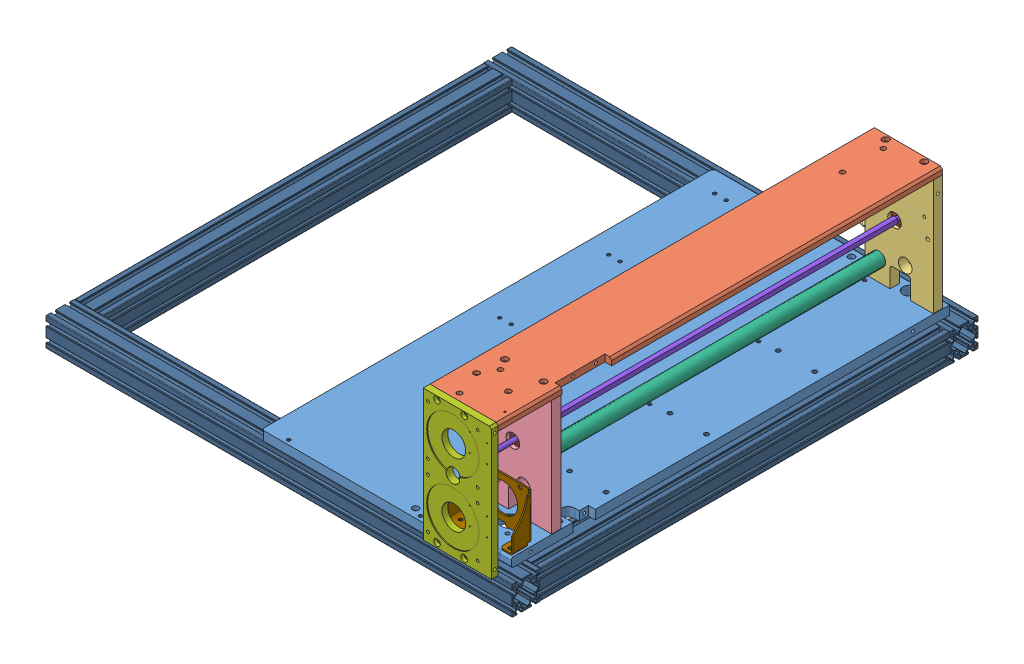
SolidWorks assembly A_Master_01, configuration Default. Lengths in mm.
Overall size (652 224.23 660.12).
12 component instances, 11 part files, 31 mates.
Components (placement in the parent):
- A0004-1: A0004 [Default] at origin size (330.5 12.8 632)
- A0001-1: A0001 [Default] at (329.875 174.68 -622.9) x (0 0 1) z (-1 0 0) size (621.59 12.05 95.3)
- A0002-2: A0002 [Default] at (0 12.8 0) x (-1 0 0) z (0 1 0) size (108.85 12.8 161.88)
- A0003-1: A0003 [Leadscrew variant] at (0 12.8 0) x (-1 0 0) z (0 1 0) size (108.85 12.8 161.88)
- A0006-1: A0006 [Default] at (254.9661 28.7444 0) x (0 0 1) z (-0.993705 -0.112029 0) size (526.19 19.05 19.05)
- A0007-1: A0007 [Default] at (254.9661 28.7444 0) x (0 0 1) z (-0.993705 -0.112029 0) size (527.84 19.05 19.05)
- A0005-1: A0005 [Default] at (234.465 -0.07 -1.31) size (95.41 184.3 9.43)
- A0020-1: A0020 [Default] at (275.57 98.905 -26.7385) size (6.32 6.32 597.2)
- LeadscrewMotorMount^A_Master_01-1: LeadscrewMotorMount^A_Master_01 [Default] at origin size (90 67.34 41.5) (virtual)
- Base-Extrusion^A_Master_01-1: Base-Extrusion^A_Master_01 [Default<As Machined>] at origin size (652 40 652) (virtual)
- 1-4x3-4x9-32_2342K184-1: 1-4x3-4x9-32_2342K184 [2342K184] at (275.57 98.905 -618.0167) x (0.965658 0.259817 0) z (0 0 1) size (19.05 19.05 7.14)
- 1-4x3-4x9-32_2342K184-2: 1-4x3-4x9-32_2342K184 [2342K184] at (275.57 98.905 -84.5865) x (0.989428 0.145025 0) z (0 0 1) size (19.05 19.05 7.14)
Mates (geometry in assembly coordinates):
- Coincident1: coincident aligned: plane of A0004-1 through (0 0 0) normal (0 0 1); plane of assembly through (0 0 0) normal (0 0 1)
- Coincident2: coincident aligned: plane of A0004-1 through (0 0 0) normal (0 1 0); plane of assembly through (0 0 0) normal (0 1 0)
- Coincident3: coincident aligned: plane of A0004-1 through (0 0 0) normal (1 0 0); plane of assembly through (0 0 0) normal (1 0 0)
- InPlace1: in place: plane of ? through (0 12.8 0) normal (0 1 0); plane of ? through (0 12.8 0) normal (0 1 0); moOrthogonalPlaneRef_w of ? through (0 12.8 0) normal (0 1 0); unknown of ?; plane of ? through (0 12.8 0) normal (0 1 0); line of ? through (-55 0 12.8) axis (0 -1 0); plane of ? through (0 12.8 0) normal (0 1 0); unknown of ?
- Coincident4: coincident aligned: plane of A0004-1; plane of A0002-2
- Coincident5: coincident aligned: moOrthogonalPlaneRef_w of A0004-1 through (0 12.8 0) normal (0 0 1); plane of A0002-2
- Coincident6: coincident anti-aligned: moOrthogonalPlaneRef_w of A0004-1 through (0 12.8 0) normal (1 0 0); plane of A0002-2
- Coincident7: coincident anti-aligned: plane of A0001-1 through (234.575 174.68 -622.9) normal (0 -1 0); plane of A0002-2 through (329.875 174.68 -610.1) normal (0 1 0)
- Coincident8: coincident aligned: plane of A0001-1 through (329.875 184.23 -622.9) normal (0 0 -1); plane of A0002-2 through (234.625 174.68 -622.9) normal (0 0 -1)
- Coincident9: coincident aligned: plane of A0001-1 through (329.875 184.23 -622.9) normal (1 0 0); plane of A0002-2 through (329.875 174.68 -610.1) normal (1 0 0)
- InPlace2: in place: plane of ? through (0 12.8 0) normal (0 1 0); plane of ? through (0 12.8 0) normal (0 1 0); plane of ? through (0 12.8 0) normal (0 1 0); unknown of ?; plane of ? through (0 12.8 0) normal (0 1 0); line of ? through (-55 0 12.8) axis (0 -1 0); plane of ? through (0 12.8 0) normal (0 1 0); unknown of ?
- Coincident10: coincident aligned: plane of A0004-1; plane of A0003-1
- Coincident11: coincident aligned: moOrthogonalPlaneRef_w of A0004-1 through (0 12.8 0) normal (0 0 1); plane of A0003-1
- Coincident12: coincident anti-aligned: moOrthogonalPlaneRef_w of A0004-1 through (0 12.8 0) normal (1 0 0); plane of A0003-1
- InPlace3: in place: plane of ? through (254.9661 28.7444 0) normal (-0.993705 -0.112029 0); line of ? through (-55 254.9661 28.7444) axis (0 -0.112029 0.993705); unknown of ?; unknown of ?
- Coincident13: coincident aligned: plane of A0006-1; plane of assembly
- Coincident14: coincident aligned: line of ? through (-10.4775 254.9661 28.7444) axis (0 -0.112029 0.993705)
- Coincident15: coincident anti-aligned: unknown of ?
- InPlace4: in place: plane of ? through (254.9661 28.7444 0) normal (-0.993705 -0.112029 0); line of ? through (-55 254.9661 28.7444) axis (0 -0.112029 0.993705); unknown of ?; unknown of ?
- Coincident16: coincident aligned: plane of A0007-1; plane of assembly
- Coincident17: coincident aligned: line of ? through (-10.4775 254.9661 28.7444) axis (0 -0.112029 0.993705)
- Coincident18: coincident anti-aligned: unknown of ?
- Coincident10: coincident aligned: plane of A0001-1 through (234.575 184.23 -622.9) normal (0 1 0); plane of A0005-1 through (234.465 184.23 8.12) normal (0 1 0)
- Coincident11: coincident aligned: plane of A0001-1 through (329.875 184.23 -90.26) normal (1 0 0); plane of A0005-1 through (329.875 184.23 8.12) normal (1 0 0)
- Coincident12: coincident anti-aligned: plane of A0001-1 through (329.875 184.23 -1.31) normal (0 0 1); plane of A0005-1 through (234.465 -0.07 -1.31) normal (0 0 -1)
- Concentric1: concentric anti-aligned: cylinder of A0002-2 through (275.57 98.905 -622.901) axis (0 0 1) radius 9.525; cylinder of A0020-1 through (275.57 98.905 -26.7385) axis (0 0 -1) radius 3.155
- Concentric2: concentric aligned: cylinder of A0002-2 through (275.57 98.905 -622.901) axis (0 0 1) radius 9.525; cylinder of 1-4x3-4x9-32_2342K184-1 through (275.57 98.905 -614.4448) axis (0 0 1) radius 9.525
- Concentric3: concentric aligned: cylinder of ? through (275.57 98.905 -88.901) axis (0 0 1) radius 9.525; cylinder of 1-4x3-4x9-32_2342K184-2 through (275.57 98.905 -81.0146) axis (0 0 1) radius 3.175
- Axis2: unknown: cylinder of ? through (240.925 153.29 -613.42) axis (0 0 1) radius 5.09; line of A0001-1; unknown of A0001-1; unknown of ?; unknown of ?; unknown of ?; unknown of ?; unknown of ?; unknown of ?; unknown of ?; unknown of ?; unknown of ?; unknown of ?; unknown of ?; unknown of ?; unknown of ?; unknown of ?; unknown of ?; unknown of ?; unknown of ?; unknown of ?; unknown of ?; unknown of ?; unknown of ?; unknown of ?; unknown of ?; unknown of ?; unknown of ?; unknown of ?; unknown of ?; unknown of ?; unknown of ?; unknown of ?; unknown of ?; unknown of ?; unknown of ?; unknown of ?; unknown of ?; unknown of A0001-1; unknown of A0001-1; unknown of ?; unknown of A0001-1; unknown of A0001-1; unknown of ?; unknown of ?; unknown of ?; unknown of ?; unknown of ?; unknown of ?; unknown of ?; unknown of ?; unknown of ?; unknown of ?; unknown of ?; unknown of ?; unknown of ?; unknown of ?; sketch_entity of ?; unknown of ?; unknown of ?; unknown of ?; unknown of ?; unknown of ?; unknown of ?; unknown of ?; unknown of ?; unknown of ?; unknown of ?; unknown of ?; unknown of ?; unknown of ?; unknown of ?; unknown of ?; unknown of ?
- PLANE3: unknown = 20 mm: plane of ? through (0 0 0) normal (0 -1 0)
- Sketch2: unknown: unknown of ?; unknown of ?; unknown of ?; unknown of ?
